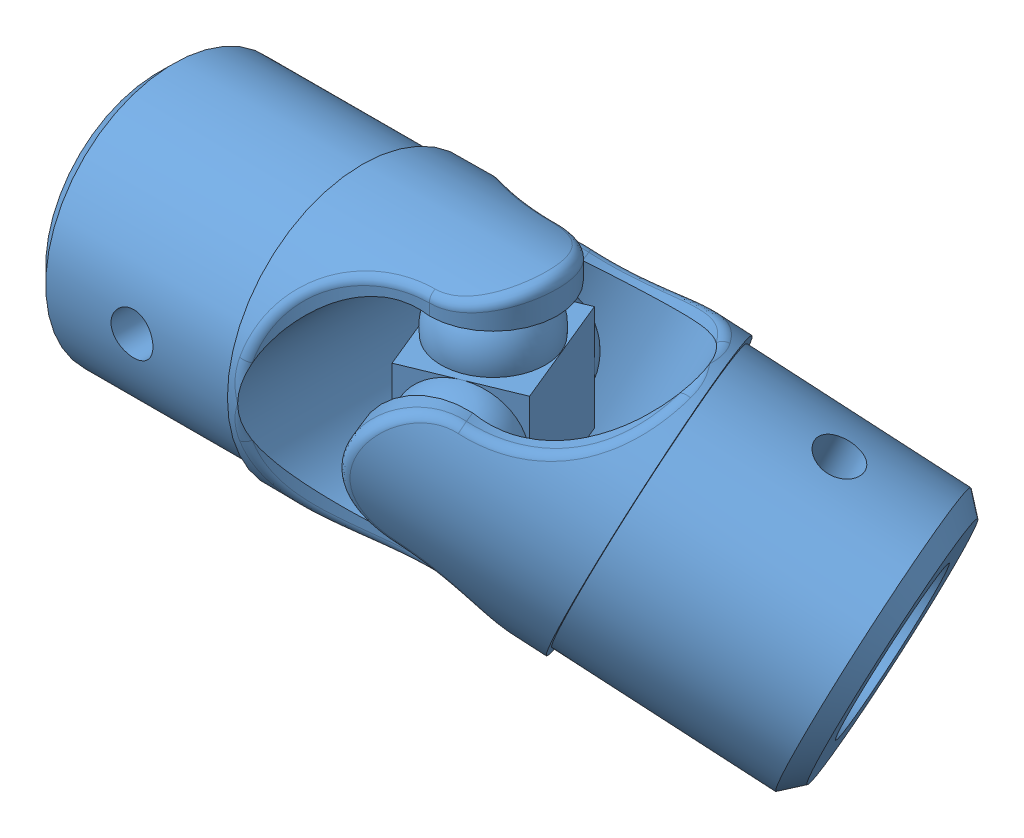
SolidWorks assembly 60625K950_Ball-And-Socket U-Joint, configuration Default. Lengths in mm.
Overall size (53.85 31.08 32.11).
3 component instances, 1 part files, 6 mates.
Components (placement in the parent):
- 60625K950_BALL-AND-SOCKET U-JOINT-1: 60625K950_BALL-AND-SOCKET U-JOINT [60625K95] at origin size (29.78 20.07 20.64)
- 60625K950_BALL-AND-SOCKET U-JOINT-2: 60625K950_BALL-AND-SOCKET U-JOINT [60625K95] x (-0.842581 0.412393 0.346394) z (0.381418 0.911006 -0.156805) size (29.78 20.07 20.64)
- 60625K950_BALL-AND-SOCKET U-JOINT-3: 60625K950_BALL-AND-SOCKET U-JOINT [Ball] x (0.924891 0 -0.380233) z (-0.380233 0 -0.924891) size (7.85 16.72 16.72)
Mates (geometry in assembly coordinates):
- Concentric1: concentric: sphere of 60625K950_BALL-AND-SOCKET U-JOINT-1; sphere of 60625K950_BALL-AND-SOCKET U-JOINT-3
- Concentric2: concentric: sphere of 60625K950_BALL-AND-SOCKET U-JOINT-1; sphere of 60625K950_BALL-AND-SOCKET U-JOINT-3
- Concentric3: concentric: sphere of 60625K950_BALL-AND-SOCKET U-JOINT-2; sphere of 60625K950_BALL-AND-SOCKET U-JOINT-3
- Concentric4: concentric: sphere of 60625K950_BALL-AND-SOCKET U-JOINT-2; sphere of 60625K950_BALL-AND-SOCKET U-JOINT-3
- Concentric103: concentric aligned: cylinder of 60625K950_BALL-AND-SOCKET U-JOINT-2 through (21.0805 -10.3177 -8.6664) axis (0.842581 -0.412393 -0.346394) radius 9.525; cylinder of ? through (8.2396 -4.0328 -3.3874) axis (0.842581 -0.412393 -0.346394) radius 5.5563
- Concentric105: concentric anti-aligned: cylinder of 60625K950_BALL-AND-SOCKET U-JOINT-2 through (18.4868 1.9649 -7.6001) axis (-0.381418 -0.911006 0.156805) radius 1.5602; cylinder of ? through (16.7793 -2.1134 -6.8982) axis (0.381418 0.911006 -0.156805) radius 1.524
